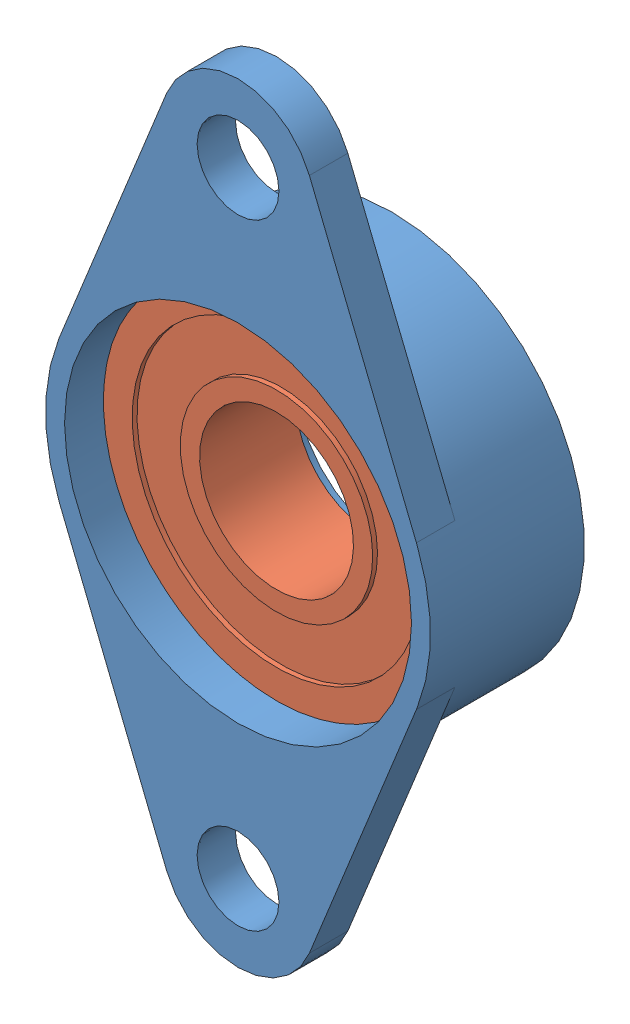
SolidWorks assembly bearing block wheel mount, configuration Default. Lengths in mm.
Overall size (40.24 63.5 12.7).
2 component instances, 2 part files, 0 mates.
Components (placement in the parent):
- bearing block wheel mount-1-1: bearing block wheel mount-1 [Default] at origin size (31.75 63.5 12.7)
- R8-ZZ-1-1: R8-ZZ-1 [Default] at (0 0 -7.1437) x (0.769224 0.638979 0) z (0 0 -1) size (28.57 28.57 7.94)
